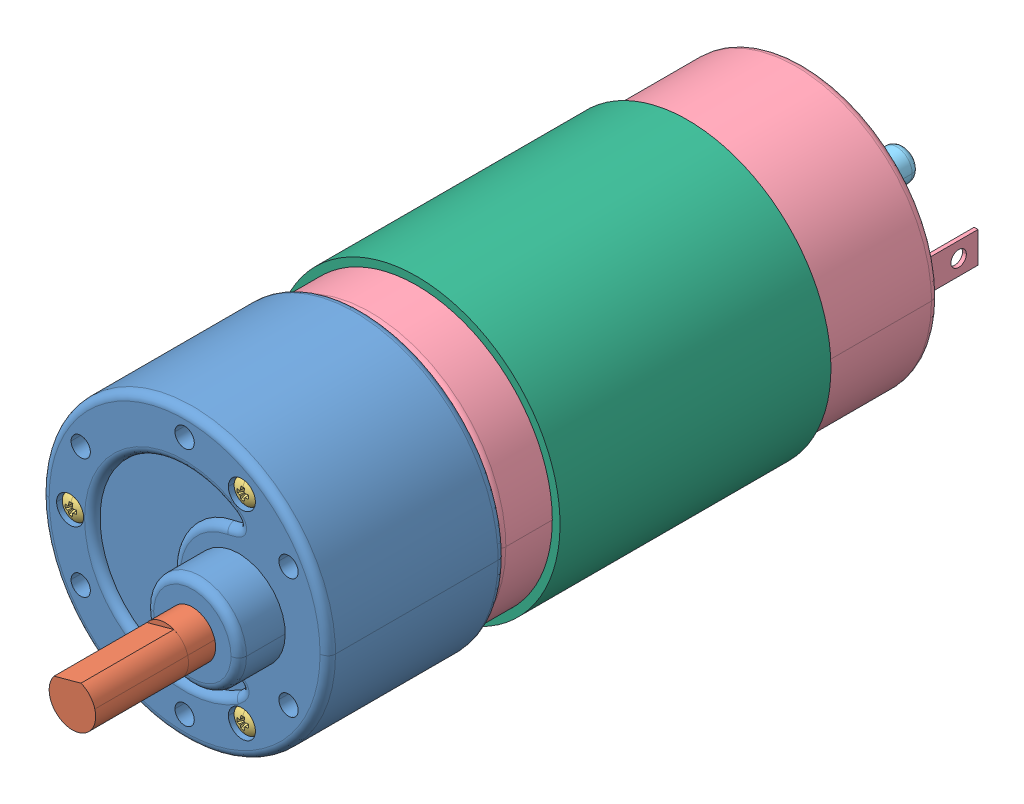
SolidWorks assembly Motor Assemply, configuration Default. Lengths in mm.
Overall size (69.73 53.38 114.51).
10 component instances, 6 part files, 0 mates.
Components (placement in the parent):
- Motor Assemply.STEP-1: Motor Assemply.STEP [Default] at origin size (69.73 53.38 114.51)
  - Motor Assemply.IGS.STEP-1: Motor Assemply.IGS.STEP [Default] at origin size (69.73 53.38 114.51)
    - Gear Box.IGS.STEP-1: Gear Box.IGS.STEP [Default] at origin size (37 51.51 29)
    - flecha.IGS.STEP-1: flecha.IGS.STEP [Default] at (7 0 19) x (0.964794 0.263005 0) z (0 0 1) size (6.01 9.01 25.51)
    - pan head cross recess screw_iso_ISO 7045 - M1.6 x 3 - Z --- 3C.IGS.STEP-1: pan head cross recess screw_iso_ISO 7045 - M1.6 x 3 - Z --- 3C.IGS.STEP [Default] at (-14.8007 0 23) x (0 0 -1) z (1 0 0) size (4.27 5 4.69)
    - pan head cross recess screw_iso_ISO 7045 - M1.6 x 3 - Z --- 3C.IGS.STEP-2: pan head cross recess screw_iso_ISO 7045 - M1.6 x 3 - Z --- 3C.IGS.STEP [Default] at (7.4004 12.8178 23) x (0 0 -1) z (1 0 0) size (4.27 5 4.69)
    - pan head cross recess screw_iso_ISO 7045 - M1.6 x 3 - Z --- 3C.IGS.STEP-3: pan head cross recess screw_iso_ISO 7045 - M1.6 x 3 - Z --- 3C.IGS.STEP [Default] at (7.4004 -12.8178 23) x (0 0 -1) z (1 0 0) size (4.27 5 4.69)
    - Body.IGS.STEP-1: Body.IGS.STEP [Default] at (0 0 -57) size (35 48.51 65)
    - 2nd Flecha.IGS.STEP-1: 2nd Flecha.IGS.STEP [Default] at (0 0 -32.5) size (4 4 75)
    - Info.IGS.STEP-1: Info.IGS.STEP [Default] at (0 0 -24.5) x (-0.045659 0.998957 0) z (0 0 1) size (37.64 68.08 35.67)
